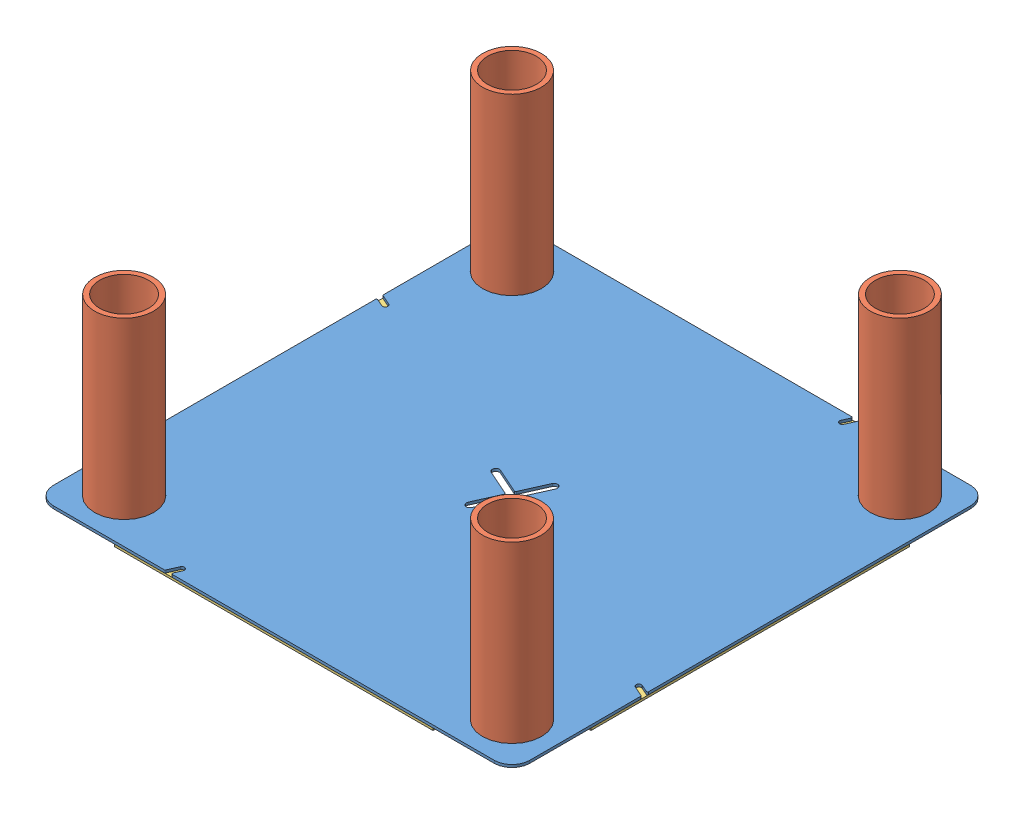
SolidWorks assembly GE-22303, configuration Default. Lengths in mm.
Overall size (341.88 128.59 341.88).
10 component instances, 3 part files, 15 mates.
Components (placement in the parent):
- GE-22304-1: GE-22304 [Default] at (0 1.5875 0) size (341.88 127 341.88)
  - GE-22304-01-1: GE-22304-01 [Default] at origin size (341.88 1.9 341.88)
  - GE-22304-02-1: GE-22304-02 [Default] at (-139.192 0 -139.192) size (42.16 127 42.16)
  - GE-22304-02-2: GE-22304-02 [Default] at (139.192 0 -139.192) size (42.16 127 42.16)
  - GE-22304-02-3: GE-22304-02 [Default] at (139.192 0 139.192) size (42.16 127 42.16)
  - GE-22304-02-4: GE-22304-02 [Default] at (-139.192 0 139.192) size (42.16 127 42.16)
- Hook_2_9-1: Hook_2_9 [Default] at (114.3 0 120.142) x (1 0 0) z (0 1 0) size (228.6 50.8 1.59)
- Hook_2_9-2: Hook_2_9 [Default] at (170.942 0 114.3) x (0 0 1) z (0 1 0) size (228.6 50.8 1.59)
- Hook_2_9-3: Hook_2_9 [Default] at (114.3 0 -170.942) x (1 0 0) z (0 1 0) size (228.6 50.8 1.59)
- Hook_2_9-4: Hook_2_9 [Default] at (-120.142 0 114.3) x (0 0 1) z (0 1 0) size (228.6 50.8 1.59)
Mates (geometry in assembly coordinates):
- Coincident1: coincident anti-aligned: plane of GE-22304-1/GE-22304-01-1 through (0 1.5875 0) normal (0 -1 0); plane of Hook_2_9-1 through (114.3 1.5875 120.142) normal (0 1 0)
- Coincident2: coincident aligned: plane of floorAssembly_baseV5-1/baseplate_baseV5-1 through (170.942 3.4849 170.942) normal (0 0 1); plane of Hook_2_9-1 through (114.3 1.5875 170.942) normal (0 0 1)
- Symmetric1: symmetric aligned: plane of Hook_2_9-1 through (114.3 1.5875 120.142) normal (1 0 0); plane of Hook_2_9-1 through (-114.3 1.5875 120.142) normal (-1 0 0)
- Coincident3: coincident anti-aligned: plane of GE-22304-1/GE-22304-01-1 through (0 1.5875 0) normal (0 -1 0); plane of Hook_2_9-4 through (-120.142 1.5875 114.3) normal (0 1 0)
- Coincident4: coincident anti-aligned: plane of GE-22304-1/GE-22304-01-1 through (0 1.5875 0) normal (0 -1 0); plane of Hook_2_9-2 through (170.942 1.5875 114.3) normal (0 1 0)
- Coincident5: coincident anti-aligned: plane of GE-22304-1/GE-22304-01-1 through (0 1.5875 0) normal (0 -1 0); plane of Hook_2_9-3 through (114.3 1.5875 -170.942) normal (0 1 0)
- Coincident6: coincident aligned: plane of floorAssembly_baseV5-1/baseplate_baseV5-1 through (170.942 3.4849 -170.942) normal (0 0 -1); plane of Hook_2_9-3 through (114.3 1.5875 -170.942) normal (0 0 -1)
- Coincident7: coincident aligned: plane of floorAssembly_baseV5-1/baseplate_baseV5-1 through (170.942 3.4849 -170.942) normal (1 0 0); plane of Hook_2_9-2 through (170.942 1.5875 114.3) normal (1 0 0)
- Coincident8: coincident aligned: plane of floorAssembly_baseV5-1/baseplate_baseV5-1 through (-170.942 3.4849 -170.942) normal (-1 0 0); plane of Hook_2_9-4 through (-170.942 1.5875 114.3) normal (-1 0 0)
- Coincident9: coincident aligned: plane of Hook_2_9-2 through (170.942 1.5875 114.3) normal (0 0 1); plane of Hook_2_9-4 through (-120.142 1.5875 114.3) normal (0 0 1)
- Coincident10: coincident aligned: plane of Hook_2_9-1 through (-114.3 1.5875 120.142) normal (-1 0 0); plane of Hook_2_9-3 through (-114.3 1.5875 -170.942) normal (-1 0 0)
- Symmetric2: symmetric aligned: plane of Hook_2_9-4 through (-120.142 1.5875 114.3) normal (0 0 1); plane of Hook_2_9-4 through (-120.142 1.5875 -114.3) normal (0 0 -1)
- Coincident11: coincident aligned: plane of GE-22304-1 through (0 1.5875 0) normal (0 0 1)
- Coincident12: coincident aligned: plane of GE-22304-1 through (0 1.5875 0) normal (1 0 0)
- Coincident13: coincident anti-aligned: plane of Hook_2_9-2 through (170.942 0 114.3) normal (0 -1 0)
